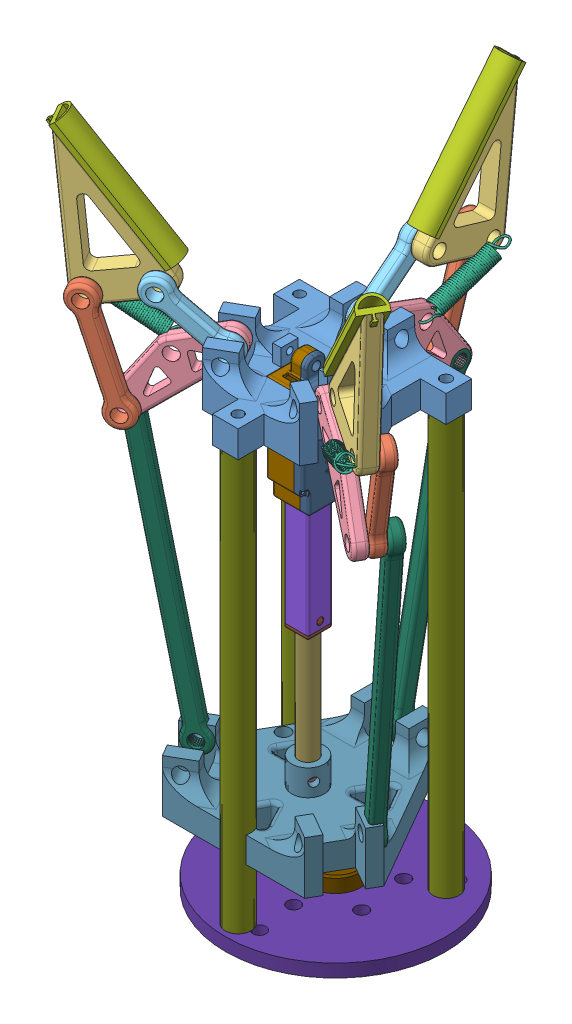
SolidWorks assembly MechanicalGripper, configuration Default. Lengths in mm.
Overall size (206.77 327.27 189.96).
38 component instances, 18 part files, 29 mates.
Components (placement in the parent):
- Base-1: Base [Default] at (29.1 37.1493 110.8136) size (84.55 26.4 78.57)
- Finger-1: Finger [Default] at (1.6508 -31.1892 224.8059) x (0.947006 0.199204 -0.251987) z (-0.13356 0.957644 0.255108) size (67.3 44.6 128.41)
  - 7.3mmLink-1: 7.3mmLink [Default] at (1.7597 112.3223 79.7725) x (0.080937 -0.137777 -0.987151) z (-0.963475 -0.264472 -0.042084) size (61.38 6.6 13.2)
  - EndLink-3: EndLink [Default] at (-2.9163 106.3709 75.6986) x (-0.116128 -0.188547 -0.975174) z (0.959869 0.231037 -0.158976) size (76.63 8.38 40.37)
  - TriLink1-5: TriLink1 [Default] at (27.3419 112.7045 61.8309) x (-0.957326 -0.271867 -0.098056) z (0.135503 -0.122541 -0.98317) size (60.28 6.6 30.89)
  - 5mmLink-4: 5mmLink [Default] at (30.379 120.5143 83.1032) x (0.602782 0.032457 -0.797245) z (-0.755968 -0.296437 -0.583641) size (46.2 6.6 13.2)
  - 9654K127_STEEL EXTENSION SPRING-1: 9654K127_STEEL EXTENSION SPRING [9654K127] at (11.6747 121.3707 71.4906) x (0.777146 0 -0.62932) z (0.62932 0 0.777146) size (44.45 7.99 8.44)
  - SoftFinger-1: SoftFinger [Default] at (3.5306 127.6837 154.9742) x (-0.255276 0.954501 -0.15415) z (0.420777 -0.033869 -0.906532) size (12.7 10.74 68.58)
- Finger-2: Finger [Default] at (150.2161 -31.274 62.2935) x (-0.69147 0.200622 -0.693988) z (0.288954 0.957278 -0.01117) size (67.3 44.6 128.41)
  - 7.3mmLink-1: 7.3mmLink [Default] at (1.7597 112.3223 79.7725) x (0.080937 -0.137777 -0.987151) z (-0.963475 -0.264472 -0.042084) size (61.38 6.6 13.2)
  - EndLink-3: EndLink [Default] at (-2.9163 106.3709 75.6986) x (-0.116128 -0.188547 -0.975174) z (0.959869 0.231037 -0.158976) size (76.63 8.38 40.37)
  - TriLink1-5: TriLink1 [Default] at (27.3419 112.7045 61.8309) x (-0.957326 -0.271867 -0.098056) z (0.135503 -0.122541 -0.98317) size (60.28 6.6 30.89)
  - 5mmLink-4: 5mmLink [Default] at (30.379 120.5143 83.1032) x (0.602782 0.032457 -0.797245) z (-0.755968 -0.296437 -0.583641) size (46.2 6.6 13.2)
  - 9654K127_STEEL EXTENSION SPRING-1: 9654K127_STEEL EXTENSION SPRING [9654K127] at (11.6747 121.3707 71.4906) x (0.777146 0 -0.62932) z (0.62932 0 0.777146) size (44.45 7.99 8.44)
  - SoftFinger-1: SoftFinger [Default] at (3.5306 127.6837 154.9742) x (-0.255276 0.954501 -0.15415) z (0.420777 -0.033869 -0.906532) size (12.7 10.74 68.58)
- Finger-3: Finger [Default] at (-64.6866 -31.9255 16.0356) x (-0.255276 0.211615 0.943426) z (-0.15415 0.954366 -0.255779) size (67.3 44.6 128.41)
  - 7.3mmLink-1: 7.3mmLink [Default] at (1.7597 112.3223 79.7725) x (0.080937 -0.137777 -0.987151) z (-0.963475 -0.264472 -0.042084) size (61.38 6.6 13.2)
  - EndLink-3: EndLink [Default] at (-2.9163 106.3709 75.6986) x (-0.116128 -0.188547 -0.975174) z (0.959869 0.231037 -0.158976) size (76.63 8.38 40.37)
  - TriLink1-5: TriLink1 [Default] at (27.3419 112.7045 61.8309) x (-0.957326 -0.271867 -0.098056) z (0.135503 -0.122541 -0.98317) size (60.28 6.6 30.89)
  - 5mmLink-4: 5mmLink [Default] at (30.379 120.5143 83.1032) x (0.602782 0.032457 -0.797245) z (-0.755968 -0.296437 -0.583641) size (46.2 6.6 13.2)
  - 9654K127_STEEL EXTENSION SPRING-1: 9654K127_STEEL EXTENSION SPRING [9654K127] at (11.6747 121.3707 71.4906) x (0.777146 0 -0.62932) z (0.62932 0 0.777146) size (44.45 7.99 8.44)
  - SoftFinger-1: SoftFinger [Default] at (3.5306 127.6837 154.9742) x (-0.255276 0.954501 -0.15415) z (0.420777 -0.033869 -0.906532) size (12.7 10.74 68.58)
- LA1-1: LA1 [Default] at (-24.2314 -21.2731 101.3715) size (20.03 181.85 20.21) (flexible)
  - EXTENSION_10404_50MM-1: EXTENSION_10404_50MM [Default] at (53.1112 29.844 1.29) size (12 60 12)
  - CLAMSHELL_BOT_10654-1: CLAMSHELL_BOT_10654 [Default] at (53.1112 76.244 -7.21) x (0 0 -1) z (0 -1 0) size (20 14.51 62.21)
  - CLAMSHELL_TOP_10653-1: CLAMSHELL_TOP_10653 [Default] at (53.1112 76.244 -7.21) x (0 0 -1) z (0 -1 0) size (20.21 11.32 62)
  - GUIDE_10429-1: GUIDE_10429 [Default] at (53.1112 -32.156 1.29) x (0 0 -1) z (-1 0 0) size (12 7.21 12)
  - SHAFT_10409_50MM2-1: SHAFT_10409_50MM2 [Default] at (53.1112 -30.6006 1.29) x (0.720438 0 0.69352) z (-0.69352 0 0.720438) size (8.95 58 8.95)
  - PLUG_10428-1: PLUG_10428 [Default] at (53.1112 -95.6006 1.29) x (0.866025 0 0.5) z (0.5 0 -0.866025) size (9 14 9.15)
- BottomPLate-1: BottomPLate [Default] at (28.8798 -136.762 120.7478) size (98.23 25.77 85.07)
- 14mmLink-1: 14mmLink [Default] at (36.379 -96.5863 57.4747) x (0 0.982213 -0.187772) z (0 0.187772 0.982213) size (157.37 6.6 13.2)
- 14mmLink-2: 14mmLink [Default] at (-12.1556 -96.5258 121.2916) x (-0.146057 0.985676 0.084326) z (-0.85362 -0.168652 0.492838) size (157.37 6.6 13.2)
- 14mmLink-3: 14mmLink [Default] at (76.6394 -96.5328 109.7254) x (0.148053 0.985278 0.085479) z (0.853276 -0.170957 0.492639) size (157.37 6.6 13.2)
- SupportTube-1: SupportTube [Default] at (65.023 41.2418 71.0961) x (0 -1 0) z (-0.122481 0 0.992471) size (203.2 12.7 12.7)
- SupportTube-2: SupportTube [Default] at (-6.859 41.2418 71.0961) x (0 -1 0) z (0.122293 0 0.992494) size (203.2 12.7 12.7)
- SupportTube-3: SupportTube [Default] at (29.0365 41.2418 137.1361) x (0 -1 0) z (0 0 1) size (203.2 12.7 12.7)
- WristPlate-1: WristPlate [Default] at (31.7141 -161.9582 91.9356) x (0.992003 0 -0.126212) z (-0.126212 0 -0.992003) size (107.95 6.35 107.95)
- Circular_Hub-2: Circular_Hub [Default] at (31.7141 -155.2732 91.9356) x (0 1 0) z (0.178492 0 0.983941) size (19.05 57.15 57.15)
Mates (geometry in assembly coordinates):
- Concentric4: concentric aligned: cylinder of Base-1 through (45.0258 59.471 102.6615) axis (-1 0 0) radius 1.65; cylinder of LA1-1/CLAMSHELL_BOT_10654-1 through (32.8798 59.471 102.6615) axis (-1 0 0) radius 2.125
- Coincident5: coincident anti-aligned: plane of Base-1 through (19.8798 62.8238 106.8525) normal (1 0 0); plane of LA1-1/CLAMSHELL_BOT_10654-1 through (19.8798 54.971 114.1615) normal (-1 0 0)
- Parallel1: parallel aligned: plane of Base-1 through (19.8798 62.8238 98.4705) normal (0 0 -1); plane of LA1-1/CLAMSHELL_BOT_10654-1 through (19.8798 54.971 94.1615) normal (0 0 -1)
- Parallel2: parallel aligned: plane of Base-1 through (5.2159 54.4418 130.8731) normal (0 0 1); plane of BottomPLate-1 through (-6.0166 -120.3507 139.23) normal (0 0 1)
- Concentric6: concentric anti-aligned: cylinder of BottomPLate-1 through (77.9973 -113.7507 60.756) axis (-1 0 0) radius 3.3; cylinder of 14mmLink-1 through (28.079 -113.7507 60.756) axis (1 0 0) radius 3.3
- Concentric8: concentric anti-aligned: cylinder of BottomPLate-1 through (20.7026 -113.7507 172.3092) axis (-0.5 0 -0.866025) radius 3.3; cylinder of 14mmLink-2 through (-13.7532 -113.7507 112.6299) axis (0.5 0 0.866025) radius 3.3
- Concentric10: concentric anti-aligned: cylinder of BottomPLate-1 through (98.4539 -113.7507 65.9667) axis (-0.5 0 0.866025) radius 3.3; cylinder of 14mmLink-3 through (69.9022 -113.7507 115.4197) axis (0.5 0 -0.866025) radius 3.3
- Concentric15: concentric anti-aligned: cylinder of LA1-1/SHAFT_10409_50MM2-1 through (28.8798 -51.8737 102.6615) axis (0 -1 0) radius 4.475; cylinder of BottomPLate-1 through (28.8798 -132.9237 102.6615) axis (0 1 0) radius 4.6355
- Concentric16: concentric aligned: cylinder of Base-1 through (26.429 61.0418 154.4152) axis (-0.5 0 -0.866025) radius 3.3; cylinder of Finger-1/5mmLink-4 through (7.6317 61.0418 121.8573) axis (-0.5 0 -0.866025) radius 3.3
- Coincident18: coincident anti-aligned: plane of Base-1 through (1.9159 67.6418 125.1573) normal (-0.5 0 -0.866025); plane of Finger-1/5mmLink-4 through (-3.3546 85.4228 128.2002) normal (0.5 0 0.866025)
- Concentric17: concentric aligned: cylinder of Finger-1/TriLink1-5 through (-32.0685 28.3545 129.5362) axis (0.5 0 0.866025) radius 3.3; cylinder of 14mmLink-2 through (-34.8103 28.3545 124.7873) axis (0.5 0 0.866025) radius 3.3
- Concentric18: concentric anti-aligned: cylinder of Finger-3/TriLink1-5 through (34.679 27.8553 33.6849) axis (-1 0 0) radius 3.3; cylinder of 14mmLink-1 through (28.079 27.8553 33.6849) axis (1 0 0) radius 3.3
- Concentric19: concentric anti-aligned: cylinder of Base-1 through (67.2051 61.0418 71.4731) axis (-1 0 0) radius 3.3; cylinder of Finger-3/5mmLink-4 through (21.479 61.0418 71.4731) axis (1 0 0) radius 3.3
- Coincident19: coincident anti-aligned: plane of Base-1 through (21.479 67.6418 78.0731) normal (1 0 0); plane of Finger-3/5mmLink-4 through (21.479 85.254 58.4681) normal (-1 0 0)
- Concentric21: concentric aligned: cylinder of Finger-2/TriLink1-5 through (84.6471 28.2973 139.1747) axis (0.5 0 -0.866025) radius 3.3; cylinder of 14mmLink-3 through (91.2471 28.2973 127.7432) axis (0.5 0 -0.866025) radius 3.3
- Concentric22: concentric aligned: cylinder of Base-1 through (79.4024 61.0418 71.9152) axis (-0.5 0 0.866025) radius 3.3; cylinder of Finger-2/5mmLink-4 through (58.1894 61.0418 108.6573) axis (-0.5 0 0.866025) radius 3.3
- Coincident20: coincident anti-aligned: plane of Base-1 through (52.4736 67.6418 105.3573) normal (-0.5 0 0.866025); plane of Finger-2/5mmLink-4 through (69.2073 85.4037 115.0185) normal (0.5 0 -0.866025)
- Coincident21: coincident anti-aligned: plane of 14mmLink-3 through (61.8901 -104.3354 110.7939) normal (-0.5 0 0.866025); plane of Finger-2/7.3mmLink-1 through (92.475 70.1547 128.4521) normal (0.5 0 -0.866025)
- Concentric27: concentric anti-aligned: cylinder of LA1-1/PLUG_10428-1 through (32.7769 -113.8737 104.9115) axis (-0.866025 0 -0.5) radius 2.125; cylinder of BottomPLate-1 through (-28.9618 -113.8737 69.2667) axis (0.866025 0 0.5) radius 2.159
- Coincident22: coincident anti-aligned: plane of Base-1 through (29.1 41.2418 106.2415) normal (0 -1 0); plane of SupportTube-1 through (65.023 41.2418 71.0961) normal (0 1 0)
- Coincident23: coincident anti-aligned: plane of Base-1 through (29.1 41.2418 106.2415) normal (0 -1 0); plane of SupportTube-2 through (-6.859 41.2418 71.0961) normal (0 1 0)
- Coincident24: coincident anti-aligned: plane of Base-1 through (29.1 41.2418 106.2415) normal (0 -1 0); plane of SupportTube-3 through (29.0365 41.2418 137.1361) normal (0 1 0)
- Concentric31: concentric aligned: cylinder of Base-1 through (29.0365 41.2418 137.1361) axis (0 1 0) radius 2.551; cylinder of SupportTube-3 through (29.0365 -161.9582 137.1361) axis (0 1 0) radius 3.175
- Concentric32: concentric aligned: cylinder of Base-1 through (65.023 41.2418 71.0961) axis (0 1 0) radius 2.6668; cylinder of SupportTube-1 through (65.023 -161.9582 71.0961) axis (0 1 0) radius 3.175
- Concentric33: concentric aligned: cylinder of Base-1 through (-6.859 41.2418 71.0961) axis (0 1 0) radius 2.4401; cylinder of SupportTube-2 through (-6.859 -161.9582 71.0961) axis (0 1 0) radius 3.175
- Coincident26: coincident anti-aligned: plane of SupportTube-3 through (29.0365 -161.9582 137.1361) normal (0 -1 0); plane of WristPlate-1 through (31.7141 -161.9582 91.9356) normal (0 1 0)
- Lock1: lock: unknown of SupportTube-2; unknown of WristPlate-1
- Concentric34: concentric anti-aligned: cylinder of WristPlate-1 through (31.7141 -168.3082 91.9356) axis (0 1 0) radius 53.975; cylinder of Circular_Hub-2 through (31.7141 -168.3082 91.9356) axis (0 -1 0) radius 28.575
- Coincident27: coincident anti-aligned: plane of WristPlate-1 through (31.7141 -168.3082 91.9356) normal (0 -1 0); plane of Circular_Hub-2 through (3.5979 -168.3082 97.036) normal (0 1 0)
